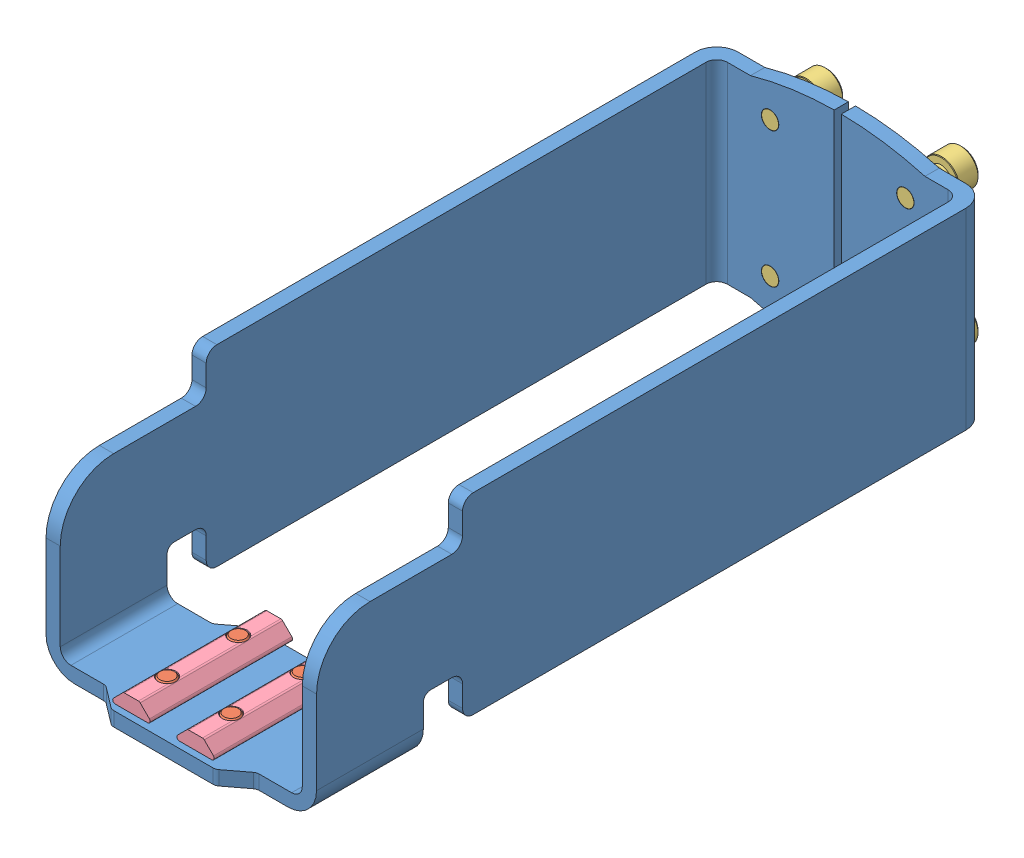
SolidWorks assembly Beugel actuator, configuration Default. Lengths in mm.
Overall size (76 67.12 205.69).
11 component instances, 4 part files, 30 mates.
Components (placement in the parent):
- 1434902 EAHA-P1-40---(part)-1: 1434902 EAHA-P1-40---(part) [Default] at (0 0 193.4) size (76 61.89 193.4)
- DIN-912 - M5x10(F)-1: DIN-912 - M5x10(F) [Default] at (9 0 183.4) x (1 0 0) z (0 0 -1) size (8.5 15.23 8.5)
- DIN-912 - M5x10(F)-2: DIN-912 - M5x10(F) [Default] at (-9 0 183.4) x (1 0 0) z (0 0 -1) size (8.5 15.23 8.5)
- DIN-912 - M5x10(F)-3: DIN-912 - M5x10(F) [Default] at (9 0 163.4) x (1 0 0) z (0 0 -1) size (8.5 15.23 8.5)
- DIN-912 - M5x10(F)-4: DIN-912 - M5x10(F) [Default] at (-9 0 163.4) x (1 0 0) z (0 0 -1) size (8.5 15.23 8.5)
- DIN-912 - M6x10(F)-1: DIN-912 - M6x10(F) [Default] at (19 12.5 -6) x (1 0 0) z (0 1 0) size (10 16.29 10)
- DIN-912 - M6x10(F)-2: DIN-912 - M6x10(F) [Default] at (-19 12.5 -6) x (1 0 0) z (0 1 0) size (10 16.29 10)
- DIN-912 - M6x10(F)-3: DIN-912 - M6x10(F) [Default] at (19 50.5 -6) x (1 0 0) z (0 1 0) size (10 16.29 10)
- DIN-912 - M6x10(F)-4: DIN-912 - M6x10(F) [Default] at (-19 50.5 -6) x (1 0 0) z (0 1 0) size (10 16.29 10)
- 1378686 EPCO-40-1: 1378686 EPCO-40 [Default] at (9 5.8 173.4) size (10.52 4 40)
- 1378686 EPCO-40-2: 1378686 EPCO-40 [Default] at (-9 5.8 173.4) size (10.52 4 40)
Mates (geometry in assembly coordinates):
- Distance1: distance = 0 mm anti-aligned: plane of 1434902 EAHA-P1-40---(part)-1 through (0 0 193.4) normal (0 1 0); plane of DIN-912 - M5x10(F)-1 through (9 0 183.4) normal (0 -1 0)
- Coincident1: coincident anti-aligned: line of 1434902 EAHA-P1-40---(part)-1 through (9 50 183.4) axis (0 -1 0); line of DIN-912 - M5x10(F)-1 through (9 -50 183.4) axis (0 1 0)
- Angle3: planar angle = 0 rad aligned: plane of DIN-912 - M5x10(F)-1 through (9 0 183.4) normal (1 0 0); plane of 1434902 EAHA-P1-40---(part)-1 through (9 0 193.4) normal (1 0 0)
- Distance2: distance = 0 mm anti-aligned: plane of 1434902 EAHA-P1-40---(part)-1 through (0 0 193.4) normal (0 1 0); plane of DIN-912 - M5x10(F)-2 through (-9 0 183.4) normal (0 -1 0)
- Coincident2: coincident anti-aligned: line of 1434902 EAHA-P1-40---(part)-1 through (-9 50 183.4) axis (0 -1 0); line of DIN-912 - M5x10(F)-2 through (-9 -50 183.4) axis (0 1 0)
- Angle6: planar angle = 0 rad aligned: plane of DIN-912 - M5x10(F)-2 through (-9 0 183.4) normal (1 0 0); plane of 1434902 EAHA-P1-40---(part)-1 through (-9 0 193.4) normal (1 0 0)
- Distance3: distance = 0 mm anti-aligned: plane of 1434902 EAHA-P1-40---(part)-1 through (0 0 193.4) normal (0 1 0); plane of DIN-912 - M5x10(F)-3 through (9 0 163.4) normal (0 -1 0)
- Coincident3: coincident anti-aligned: line of 1434902 EAHA-P1-40---(part)-1 through (9 50 163.4) axis (0 -1 0); line of DIN-912 - M5x10(F)-3 through (9 -50 163.4) axis (0 1 0)
- Angle9: planar angle = 0 rad aligned: plane of DIN-912 - M5x10(F)-3 through (9 0 163.4) normal (1 0 0); plane of 1434902 EAHA-P1-40---(part)-1 through (9 0 193.4) normal (1 0 0)
- Distance4: distance = 0 mm anti-aligned: plane of 1434902 EAHA-P1-40---(part)-1 through (0 0 193.4) normal (0 1 0); plane of DIN-912 - M5x10(F)-4 through (-9 0 163.4) normal (0 -1 0)
- Coincident4: coincident anti-aligned: line of 1434902 EAHA-P1-40---(part)-1 through (-9 50 163.4) axis (0 -1 0); line of DIN-912 - M5x10(F)-4 through (-9 -50 163.4) axis (0 1 0)
- Angle12: planar angle = 0 rad aligned: plane of DIN-912 - M5x10(F)-4 through (-9 0 163.4) normal (1 0 0); plane of 1434902 EAHA-P1-40---(part)-1 through (-9 0 193.4) normal (1 0 0)
- Distance7: distance = 6 mm anti-aligned: plane of 1434902 EAHA-P1-40---(part)-1 through (0 0 0) normal (0 0 1); plane of DIN-912 - M6x10(F)-1 through (19 12.5 -6) normal (0 0 -1)
- Coincident5: coincident anti-aligned: line of 1434902 EAHA-P1-40---(part)-1 through (19 12.5 274.3) axis (0 0 -1); line of DIN-912 - M6x10(F)-1 through (19 12.5 -56) axis (0 0 1)
- Angle15: planar angle = 0 rad aligned: plane of DIN-912 - M6x10(F)-1 through (19 12.5 -6) normal (1 0 0); plane of 1434902 EAHA-P1-40---(part)-1 through (19 0 193.4) normal (1 0 0)
- Distance10: distance = 6 mm anti-aligned: plane of 1434902 EAHA-P1-40---(part)-1 through (0 0 0) normal (0 0 1); plane of DIN-912 - M6x10(F)-2 through (-19 12.5 -6) normal (0 0 -1)
- Coincident6: coincident anti-aligned: line of 1434902 EAHA-P1-40---(part)-1 through (-19 12.5 274.3) axis (0 0 -1); line of DIN-912 - M6x10(F)-2 through (-19 12.5 -56) axis (0 0 1)
- Angle18: planar angle = 0 rad aligned: plane of DIN-912 - M6x10(F)-2 through (-19 12.5 -6) normal (1 0 0); plane of 1434902 EAHA-P1-40---(part)-1 through (-19 0 193.4) normal (1 0 0)
- Distance13: distance = 6 mm anti-aligned: plane of 1434902 EAHA-P1-40---(part)-1 through (0 0 0) normal (0 0 1); plane of DIN-912 - M6x10(F)-3 through (19 50.5 -6) normal (0 0 -1)
- Coincident7: coincident anti-aligned: line of 1434902 EAHA-P1-40---(part)-1 through (19 50.5 274.3) axis (0 0 -1); line of DIN-912 - M6x10(F)-3 through (19 50.5 -56) axis (0 0 1)
- Angle21: planar angle = 0 rad aligned: plane of DIN-912 - M6x10(F)-3 through (19 50.5 -6) normal (1 0 0); plane of 1434902 EAHA-P1-40---(part)-1 through (19 0 193.4) normal (1 0 0)
- Distance16: distance = 6 mm anti-aligned: plane of 1434902 EAHA-P1-40---(part)-1 through (0 0 0) normal (0 0 1); plane of DIN-912 - M6x10(F)-4 through (-19 50.5 -6) normal (0 0 -1)
- Coincident8: coincident anti-aligned: line of 1434902 EAHA-P1-40---(part)-1 through (-19 50.5 274.3) axis (0 0 -1); line of DIN-912 - M6x10(F)-4 through (-19 50.5 -56) axis (0 0 1)
- Angle24: planar angle = 0 rad aligned: plane of DIN-912 - M6x10(F)-4 through (-19 50.5 -6) normal (1 0 0); plane of 1434902 EAHA-P1-40---(part)-1 through (-19 0 193.4) normal (1 0 0)
- Distance17: distance = 0 mm anti-aligned: plane of 1434902 EAHA-P1-40---(part)-1 through (0 5.8 193.4) normal (0 -1 0); plane of 1378686 EPCO-40-1 through (9 5.8 173.4) normal (0 1 0)
- Coincident9: coincident anti-aligned: line of 1434902 EAHA-P1-40---(part)-1 through (9 -50 183.4) axis (0 1 0); line of 1378686 EPCO-40-1 through (9 55.8 183.4) axis (0 -1 0)
- Angle27: planar angle = 0 rad aligned: plane of 1378686 EPCO-40-1 through (9 5.8 173.4) normal (1 0 0); plane of 1434902 EAHA-P1-40---(part)-1 through (9 0 193.4) normal (1 0 0)
- Distance18: distance = 0 mm anti-aligned: plane of 1434902 EAHA-P1-40---(part)-1 through (0 5.8 193.4) normal (0 -1 0); plane of 1378686 EPCO-40-2 through (-9 5.8 173.4) normal (0 1 0)
- Coincident10: coincident anti-aligned: line of 1434902 EAHA-P1-40---(part)-1 through (-9 -50 183.4) axis (0 1 0); line of 1378686 EPCO-40-2 through (-9 55.8 183.4) axis (0 -1 0)
- Angle30: planar angle = 0 rad aligned: plane of 1378686 EPCO-40-2 through (-9 5.8 173.4) normal (1 0 0); plane of 1434902 EAHA-P1-40---(part)-1 through (-9 0 193.4) normal (1 0 0)
